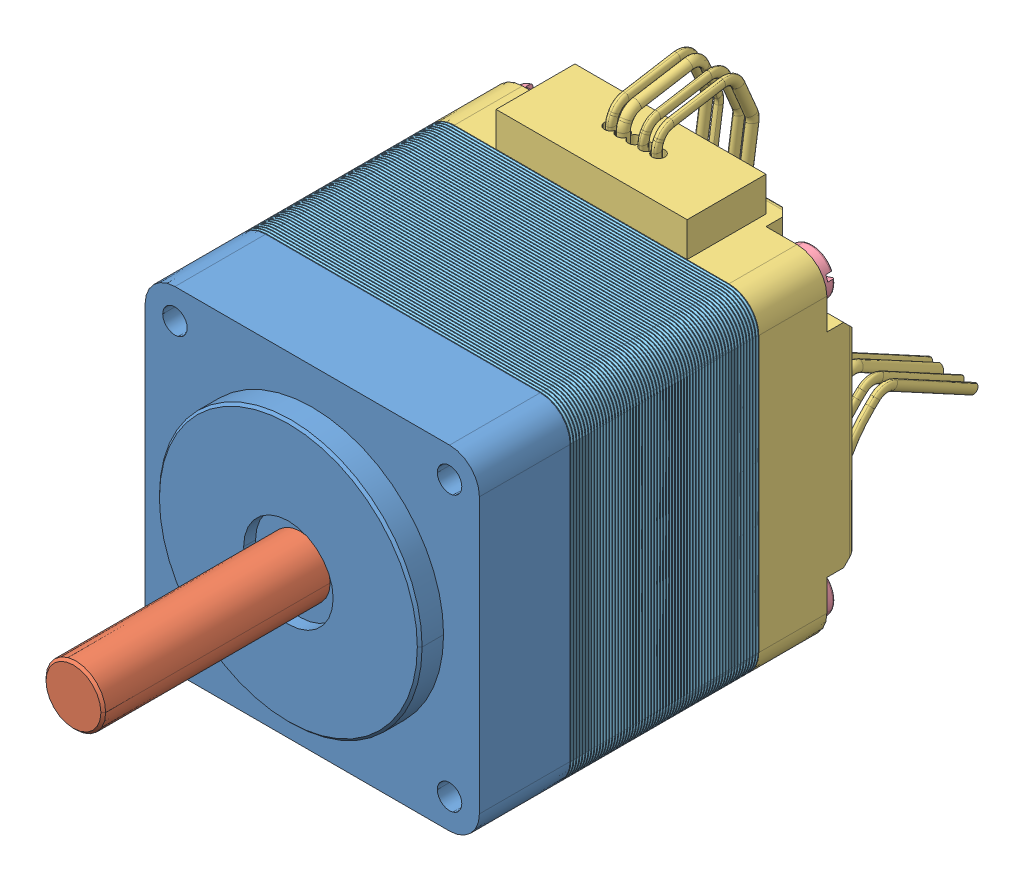
SolidWorks assembly NEMA11, configuration Default. Lengths in mm.
Overall size (29.4 34.27 73.66).
9 component instances, 5 part files, 0 mates.
Components (placement in the parent):
- NEMA11.STEP-1: NEMA11.STEP [Default] at origin size (29.4 34.27 73.66)
  - Lagerschild_11.STEP-1: Lagerschild_11.STEP [Default] at (0 0 7.4) size (28 28 9.6)
  - Welle_11.STEP-1: Welle_11.STEP [Default] at (0 0 13) size (5 5 51)
  - Kollektorschild_11.STEP-1: Kollektorschild_11.STEP [Default] at (0 0 -8.4) x (-1 0 0) z (0 0 -1) size (28 33.84 30.26)
  - Schraube_M2x25.STEP-1: Schraube_M2x25.STEP [Default] at (11.5 11.5 -14.1) x (0.310753 -0.950491 0) z (0 0 -1) size (5.15 3.8 26.3)
  - Schraube_M2x25.STEP-2: Schraube_M2x25.STEP [Default] at (11.5 -11.5 -14.1) x (0.93401 -0.357248 0) z (0 0 -1) size (5.15 3.8 26.3)
  - Schraube_M2x25.STEP-3: Schraube_M2x25.STEP [Default] at (-11.5 11.5 -14.1) x (0.994073 0.108716 0) z (0 0 -1) size (5.15 3.8 26.3)
  - Schraube_M2x25.STEP-4: Schraube_M2x25.STEP [Default] at (-11.5 -11.5 -14.1) x (0.679179 0.733972 0) z (0 0 -1) size (5.15 3.8 26.3)
  - Stator_11.STEP-1: Stator_11.STEP [Default] at (0 0 -0.5) x (-1 0 0) z (0 0 1) size (28 28 15.8)
